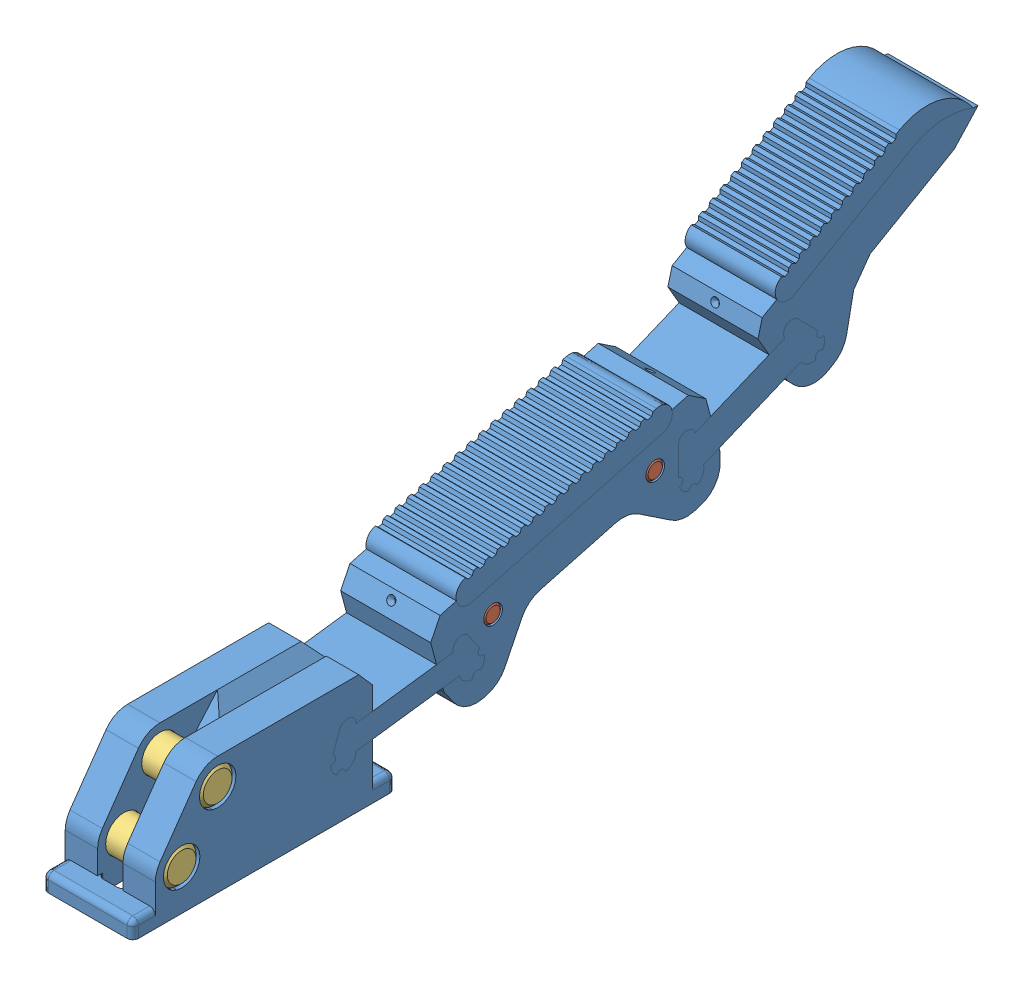
SolidWorks assembly block_finger_ff_t, configuration Default. Lengths in mm.
Overall size (16 58.08 150.14).
7 component instances, 5 part files, 12 mates.
Components (placement in the parent):
- finger_ff_t-1: finger_ff_t [Default] at origin size (16 58.08 150.14)
- 98381A472 D1-8 L5-8-1: 98381A472 D1-8 L5-8 [98381A472] at (0.0625 5.5634 -30.2193) size (15.88 3.17 3.17)
- 98381A472 D1-8 L5-8-2: 98381A472 D1-8 L5-8 [98381A472] at (0.0625 13.2775 -59.0086) size (15.88 3.17 3.17)
- 98381A539 D1-4 L5-8-1: 98381A539 D1-4 L5-8 [98381A539] at (0.0625 3.5418 18.7031) size (15.88 6.35 6.35)
- 98381A539 D1-4 L5-8-2: 98381A539 D1-4 L5-8 [98381A539] at (0.0625 -5.6082 25.11) size (15.88 6.35 6.35)
- 93365A120 4-40 insert-1: 93365A120 4-40 insert [93365A120] at (0 25.5032 -95.7226) x (1 0 0) z (0 0.812659 -0.582739) size (4.37 3.82 4.37)
- 91253A106 4-40 L1-4 countersunk-1: 91253A106 4-40 L1-4 countersunk [91253A106] at (0 24.2671 -97.4464) x (0.996599 0.066964 -0.048019) z (0 -0.582739 -0.812659) size (6.48 6.48 6.63)
Mates (geometry in assembly coordinates):
- Concentric1: concentric aligned: cylinder of finger_ff_t-1 through (-8 13.2775 -59.0086) axis (1 0 0) radius 1.6625; cylinder of 98381A472 D1-8 L5-8-2 through (-7.875 13.2775 -59.0086) axis (1 0 0) radius 1.5875
- Coincident1: coincident aligned: plane of finger_ff_t-1 through (8 0 0) normal (1 0 0); plane of 98381A472 D1-8 L5-8-2 through (8 13.2775 -59.0086) normal (1 0 0)
- Concentric2: concentric aligned: cylinder of finger_ff_t-1 through (-8 5.5634 -30.2193) axis (1 0 0) radius 1.6625; cylinder of 98381A472 D1-8 L5-8-1 through (-7.875 5.5634 -30.2193) axis (1 0 0) radius 1.5875
- Coincident2: coincident aligned: plane of finger_ff_t-1 through (8 0 0) normal (1 0 0); plane of 98381A472 D1-8 L5-8-1 through (8 5.5634 -30.2193) normal (1 0 0)
- Concentric3: concentric aligned: cylinder of finger_ff_t-1 through (-8 3.5418 18.7031) axis (1 0 0) radius 3.25; cylinder of 98381A539 D1-4 L5-8-1 through (-7.875 3.5418 18.7031) axis (1 0 0) radius 3.175
- Coincident3: coincident aligned: plane of finger_ff_t-1 through (8 0 0) normal (1 0 0); plane of 98381A539 D1-4 L5-8-1 through (8 3.5418 18.7031) normal (1 0 0)
- Concentric4: concentric aligned: cylinder of finger_ff_t-1 through (-8 -5.6082 25.11) axis (1 0 0) radius 3.25; cylinder of 98381A539 D1-4 L5-8-2 through (-7.875 -5.6082 25.11) axis (1 0 0) radius 3.175
- Coincident4: coincident aligned: plane of finger_ff_t-1 through (8 0 0) normal (1 0 0); plane of 98381A539 D1-4 L5-8-2 through (8 -5.6082 25.11) normal (1 0 0)
- Concentric5: concentric aligned: cylinder of finger_ff_t-1 through (0 28.1256 -92.0656) axis (0 -0.582739 -0.812659) radius 1.85; circle of 93365A120 4-40 insert-1
- Coincident5: coincident aligned: plane of finger_ff_t-1 through (-13 27.5349 -97.1794) normal (0 -0.582739 -0.812659); plane of 93365A120 4-40 insert-1 through (0 25.5032 -95.7226) normal (0 -0.582739 -0.812659)
- Concentric6: concentric anti-aligned: circle of 93365A120 4-40 insert-1; circle of 91253A106 4-40 L1-4 countersunk-1
- Coincident6: coincident: circle of 93365A120 4-40 insert-1; cone of 91253A106 4-40 L1-4 countersunk-1 through (0 25.4957 -95.7331) axis (0 0.582739 0.812659); plane of ?
